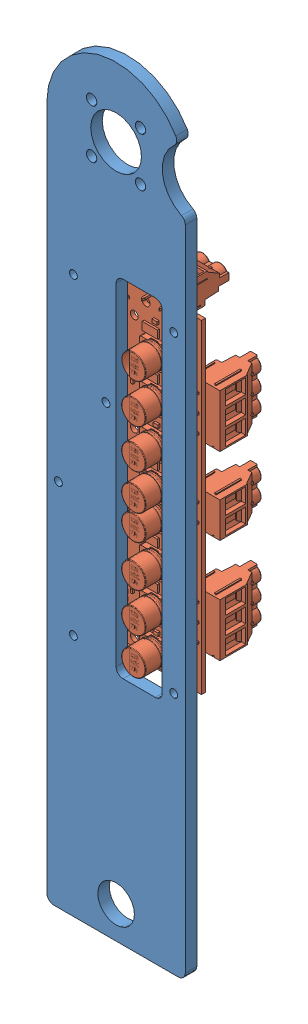
SolidWorks assembly stator_test_assy, configuration Default. Lengths in mm.
Overall size (65.31 330 34.52).
2 component instances, 2 part files, 4 mates.
Components (placement in the parent):
- motor_bracket_stator_test-1: motor_bracket_stator_test [Default] at origin size (60 330 5)
- PCBasembly_simp-1: PCBasembly_simp [Default] at (59 243.5 -4.7103) x (0 -1 0) z (0 0 -1) size (146.61 56.31 34.52)
Mates (geometry in assembly coordinates):
- Distance1: distance = 3 mm anti-aligned: plane of PCBasembly_simp-1 through (59 243.5 -3) normal (0 0 1); plane of motor_bracket_stator_test-1 through (60 330 0) normal (0 0 -1)
- Parallel1: parallel aligned: plane of motor_bracket_stator_test-1 through (0 0 0) normal (-1 0 0); plane of PCBasembly_simp-1 through (9 243.5 -3) normal (-1 0 0)
- Distance2: distance = 103 mm aligned: plane of PCBasembly_simp-1 through (9 103 -3) normal (0 -1 0); plane of motor_bracket_stator_test-1 through (60 0 0) normal (0 -1 0)
- Distance3: distance = 9 mm aligned: plane of PCBasembly_simp-1 through (9 243.5 -3) normal (-1 0 0); plane of motor_bracket_stator_test-1 through (0 0 0) normal (-1 0 0)
